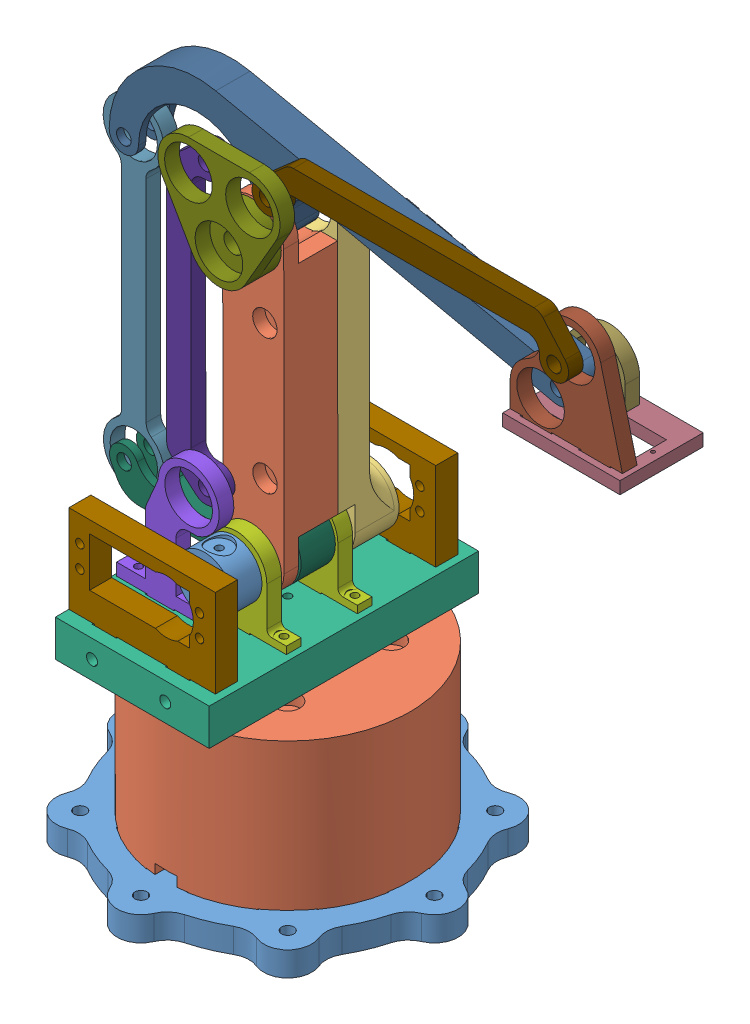
SolidWorks assembly Ensamble completo, configuration Predeterminado. Lengths in mm.
Overall size (225.72 266.26 139.5).
23 component instances, 21 part files, 60 mates.
Components (placement in the parent):
- Base_A-1: Base_A [Predeterminado] at (0.4465 -9.1301 139.5) size (139.5 10 139.5)
- Base_B-1: Base_B [Predeterminado] at (0.4465 60.8699 139.5) x (1 0 0) z (0 -1 0) size (100 100 70.09)
- Base_C-1: Base_C [Predeterminado] at (0.4465 22.8699 139.5) x (0.707107 0 0.707107) z (0 1 0) size (79 79 28)
- 30202JR-1: 30202JR [Predeterminado] at (0.4465 60.8699 139.5) x (0.837169 0 0.546944) z (0.546944 0 -0.837169) size (35 11 35)
- Eje_1_tractor-1: Eje_1_tractor [Predeterminado] at (0.4465 38.8699 139.5) x (0.999999 0 0.00137) z (-0.00137 0 0.999999) size (25 33 25)
- Eje_1_plataforma-1: Eje_1_plataforma [Predeterminado] at (0.4465 61.8699 139.5) x (-0.00137 0 0.999999) z (-0.999999 0 -0.00137) size (110 15 66)
- Soporte_eje_2-1: Soporte_eje_2 [Predeterminado] at (0.4657 97.8699 125.5) x (0.999999 0 0.00137) z (0 -1 0) size (41 6 48.5)
- Soporte_eje_2-2: Soporte_eje_2 [Predeterminado] at (0.4259 97.8699 154.5) x (0.999999 0 0.00137) z (0 -1 0) size (41 6 48.5)
- Soporte_paralelas-1: Soporte_paralelas [Predeterminado] at (0.4163 97.8699 161.5) x (0.999999 0 0.00137) z (0 -1 0) size (42 6 70.15)
- Soporte_motor-1: Soporte_motor [Predeterminado] at (20.3786 76.8699 189.0274) x (-0.999999 0 -0.00137) z (0.00137 0 -0.999999) size (60 51 9)
- Soporte_motor-2: Soporte_motor [Predeterminado] at (20.502 76.8699 99.0274) x (-0.999999 0 -0.00137) z (0.00137 0 -0.999999) size (60 51 9)
- Eje_3-1: Eje_3 [Predeterminado] at (118.0441 212.8707 132.6612) x (0.212423 0.977178 0.000291) z (-0.00137 0 0.999999) size (49.75 186.32 15)
- Eje_4_A-1: Eje_4_A [Predeterminado] at (118.0235 212.8707 147.6611) x (0.999999 -0.000184 0.00137) z (-0.00137 0 0.999999) size (46 49.15 6)
- Eje_4_B-1: Eje_4_B [Predeterminado] at (118.0537 212.8707 125.6612) x (0.999999 -0.000184 0.00137) z (-0.00137 0 0.999999) size (25 27.5 6)
- Eje_4_C-1: Eje_4_C [Predeterminado] at (105.555 197.873 122.644) x (-0.00137 0 0.999999) z (0.000184 1 0) size (34 48 5)
- Leva_eje_3-1: Leva_eje_3 [Predeterminado] at (-59.5493 97.8695 136.4178) x (0.999999 0.000852 0.00137) z (-0.00137 0 0.999999) size (25 140 6)
- Panalca_eje_3-1: Panalca_eje_3 [Predeterminado] at (0.4561 97.8699 132.5) x (-0.000007 1 0) z (-0.00137 0 0.999999) size (25 78.5 14)
- Triangulo-1: Triangulo [Predeterminado] at (0.3102 212.8699 167.4998) x (-0.999999 0 -0.00137) z (0.00137 0 -0.999999) size (50 46.65 13)
- Varilla_115mm-1: Varilla_115mm [Predeterminado] at (-12.0823 119.5205 160.4828) x (-0.999999 -0.000852 -0.00137) z (0.00137 0 -0.999999) size (22 127 6)
- Varilla_117mm-1: Varilla_117mm [Predeterminado] at (130.5179 234.519 154.6783) x (0.000012 1 0) z (-0.00137 0 0.999999) size (22 129.69 6)
- eje_3_tractor-1: eje_3_tractor [Predeterminado] at (0.3999 97.8699 173.5) x (-0.707111 0.707102 -0.000969) z (-0.707101 -0.707112 -0.000969) size (23 12 23)
- Eje_2_A-3: Eje_2_A [Predeterminado] at (0.4753 97.8699 118.5) x (0.999999 0.000852 0.00137) z (-0.00137 0 0.999999) size (25 140 32)
- Eje_2_B-3: Eje_2_B [Predeterminado] at (0.4753 97.8699 118.5) x (0.999999 0.000852 0.00137) z (-0.00137 0 0.999999) size (25 140 25)
Mates (geometry in assembly coordinates):
- Coincidente1: coincident anti-aligned: plane of Base_B-1 through (0.4465 50.8699 139.5) normal (0 -1 0); plane of Base_C-1 through (0.4465 50.8699 139.5) normal (0 1 0)
- Concéntrica4: concentric aligned: cylinder of Base_B-1 through (21.6597 60.8699 160.7132) axis (0 -1 0) radius 2; cylinder of Base_C-1 through (21.6597 50.8699 160.7132) axis (0 -1 0) radius 2
- Concéntrica5: concentric anti-aligned: cylinder of Base_A-1 through (0.4465 0.8699 139.5) axis (0 -1 0) radius 50.25; cylinder of Base_B-1 through (0.4465 -9.1301 139.5) axis (0 1 0) radius 50
- Concéntrica6: concentric aligned: cylinder of Base_A-1 through (32.2663 0.8699 171.3198) axis (0 -1 0) radius 2; cylinder of Base_B-1 through (32.2663 20.8699 171.3198) axis (0 -1 0) radius 1.5
- Coincidente2: coincident anti-aligned: plane of Base_A-1 through (0.4465 0.8699 139.5) normal (0 1 0); plane of Base_B-1 through (0.4465 0.8699 139.5) normal (0 -1 0)
- Coincidente3: coincident anti-aligned: plane of Base_C-1 through (0.4465 50.8699 139.5) normal (0 1 0); plane of 30202JR-1 through (0.4465 50.8699 139.5) normal (0 -1 0)
- Concéntrica8: concentric aligned: cylinder of Eje_1_tractor-1 through (0.4465 38.8699 139.5) axis (0 1 0) radius 1.5; cylinder of Eje_1_plataforma-1 through (0.4465 71.8699 139.5) axis (0 1 0) radius 1.5
- Paralelo2: parallel anti-aligned: plane of Eje_1_tractor-1 through (-3.3124 71.8699 145.99) normal (-0.00137 0 0.999999); plane of Eje_1_plataforma-1 through (0.4373 76.8699 146.2117) normal (0.00137 0 -0.999999)
- Coincidente5: coincident anti-aligned: plane of Eje_1_tractor-1 through (0.4465 71.8699 139.5) normal (0 1 0); plane of Eje_1_plataforma-1 through (0.4465 71.8699 139.5) normal (0 -1 0)
- Coincidente6: coincident anti-aligned: plane of 30202JR-1 through (0.4465 61.8699 139.5) normal (0 1 0); plane of Eje_1_plataforma-1 through (0.4465 61.8699 139.5) normal (0 -1 0)
- Concéntrica9: concentric aligned: cylinder of 30202JR-1 through (0.4465 38.5369 139.5) axis (0 -1 0) radius 7.5; cylinder of Eje_1_tractor-1 through (0.4465 61.8699 139.5) axis (0 -1 0) radius 7.875
- Distancia1: distance = 0.5 mm anti-aligned: plane of Soporte_motor-2 through (20.502 76.8699 99.0274) normal (-0.00137 0 0.999999); plane of Eje_1_plataforma-1 through (0.5013 76.8699 99.5) normal (0.00137 0 -0.999999)
- Coincidente8: coincident anti-aligned: plane of Eje_1_plataforma-1 through (0.4465 76.8699 139.5) normal (0 1 0); plane of Soporte_motor-2 through (20.5143 76.8699 90.0275) normal (0 -1 0)
- Concéntrica10: concentric anti-aligned: cylinder of Eje_1_plataforma-1 through (5.4876 69.3699 109.5069) axis (0.00137 0 -0.999999) radius 1.5; cylinder of Soporte_motor-2 through (5.5143 69.3699 90.0069) axis (-0.00137 0 0.999999) radius 1.5
- Distancia2: distance = 0.5 mm anti-aligned: plane of Soporte_motor-1 through (20.3786 76.8699 189.0274) normal (-0.00137 0 0.999999); plane of Eje_1_plataforma-1 through (0.378 76.8699 189.5) normal (0.00137 0 -0.999999)
- Coincidente10: coincident anti-aligned: plane of Eje_1_plataforma-1 through (0.4465 76.8699 139.5) normal (0 1 0); plane of Soporte_motor-1 through (20.391 76.8699 180.0274) normal (0 -1 0)
- Concéntrica11: concentric aligned: cylinder of Eje_1_plataforma-1 through (-24.5946 69.3699 169.4657) axis (-0.00137 0 0.999999) radius 1.5; cylinder of Soporte_motor-1 through (-24.609 69.3699 179.9657) axis (-0.00137 0 0.999999) radius 1.5
- Coincidente11: coincident anti-aligned: plane of Eje_1_plataforma-1 through (0.4465 76.8699 139.5) normal (0 1 0); plane of Soporte_eje_2-1 through (0.4575 76.8699 131.5) normal (0 -1 0)
- Concéntrica12: concentric aligned: cylinder of Eje_1_plataforma-1 through (-16.0384 76.8699 128.4774) axis (0 -1 0) radius 1.5; cylinder of Soporte_eje_2-1 through (-16.0384 82.8699 128.4774) axis (0 -1 0) radius 1.5
- Concéntrica13: concentric aligned: cylinder of Eje_1_plataforma-1 through (16.9616 76.8699 128.5226) axis (0 -1 0) radius 1.5; cylinder of Soporte_eje_2-1 through (16.9616 82.8699 128.5226) axis (0 -1 0) radius 1.5
- Coincidente12: coincident anti-aligned: plane of Eje_1_plataforma-1 through (0.4465 76.8699 139.5) normal (0 1 0); plane of Soporte_eje_2-2 through (0.4177 76.8699 160.5) normal (0 -1 0)
- Concéntrica14: concentric aligned: cylinder of Eje_1_plataforma-1 through (-16.0782 76.8699 157.4774) axis (0 -1 0) radius 1.5; cylinder of Soporte_eje_2-2 through (-16.0782 82.8699 157.4774) axis (0 -1 0) radius 1.5
- Concéntrica15: concentric aligned: cylinder of Eje_1_plataforma-1 through (16.9218 76.8699 157.5226) axis (0 -1 0) radius 1.5; cylinder of Soporte_eje_2-2 through (16.9218 82.8699 157.5226) axis (0 -1 0) radius 1.5
- Coincidente13: coincident anti-aligned: plane of Eje_1_plataforma-1 through (0.4465 76.8699 139.5) normal (0 1 0); plane of Soporte_paralelas-1 through (0.4081 76.8699 167.5) normal (0 -1 0)
- Concéntrica16: concentric anti-aligned: cylinder of Eje_1_plataforma-1 through (-35.5877 60.8699 164.4506) axis (0 1 0) radius 1.5; cylinder of Soporte_paralelas-1 through (-35.5877 82.8699 164.4506) axis (0 -1 0) radius 1.5
- Concéntrica17: concentric anti-aligned: cylinder of Eje_1_plataforma-1 through (-11.5878 60.8699 164.4835) axis (0 1 0) radius 1.5; cylinder of Soporte_paralelas-1 through (-11.5878 82.8699 164.4835) axis (0 -1 0) radius 1.5
- Coincidente32: coincident anti-aligned: plane of Eje_4_B-1 through (118.0436 202.8707 131.6612) normal (-0.000184 -1 0); plane of Eje_4_C-1 through (105.5559 202.873 122.644) normal (0.000184 1 0)
- Distancia22: distance = 0.5 mm anti-aligned: plane of Eje_4_B-1 through (122.5454 212.8699 131.6673) normal (0.999999 -0.000184 0.00137); plane of Eje_4_C-1 through (123.0429 202.8698 132.168) normal (-0.999999 0.000184 -0.00137)
- Distancia23: distance = 0.5 mm anti-aligned: plane of Eje_4_B-1 through (118.0454 212.8707 131.6612) normal (-0.00137 0 0.999999); plane of Eje_4_C-1 through (110.0429 202.8722 132.1502) normal (0.00137 0 -0.999999)
- Distancia17: distance = 0.5 mm anti-aligned: plane of Eje_4_A-1 through (134.5125 197.8677 153.6837) normal (-0.999999 0.000184 -0.00137); plane of Eje_4_C-1 through (134.0127 202.8678 154.1831) normal (0.999999 -0.000184 0.00137)
- Coincidente29: coincident anti-aligned: plane of Eje_4_A-1 through (146.5134 202.8655 153.7002) normal (-0.000184 -1 0); plane of Eje_4_C-1 through (105.5559 202.873 122.644) normal (0.000184 1 0)
- Distancia19: distance = 0.5 mm anti-aligned: plane of Eje_4_A-1 through (130.5275 234.519 147.6783) normal (0.00137 0 -0.999999); plane of Eje_4_C-1 through (134.0223 202.8678 147.1831) normal (-0.00137 0 0.999999)
- Concéntrica18: concentric aligned: cylinder of Eje_3-1 through (118.0249 212.8707 146.6611) axis (0.00137 0 -0.999999) radius 3; cylinder of Eje_4_A-1 through (118.0153 212.8707 153.6611) axis (0.00137 0 -0.999999) radius 9.75
- Distancia3: distance = 1 mm anti-aligned: plane of Eje_3-1 through (118.0249 212.8707 146.6611) normal (-0.00137 0 0.999999); plane of Eje_4_A-1 through (130.5275 234.519 147.6783) normal (0.00137 0 -0.999999)
- Concéntrica21: concentric aligned: cylinder of Triangulo-1 through (-12.1816 234.5205 161.4827) axis (-0.00137 0 0.999999) radius 9.75; cylinder of Varilla_115mm-1 through (-12.172 234.5205 154.4827) axis (-0.00137 0 0.999999) radius 3
- Distancia6: distance = 1 mm anti-aligned: plane of Varilla_115mm-1 through (-12.0823 119.5205 160.4828) normal (-0.00137 0 0.999999); plane of Triangulo-1 through (0.3184 212.8699 161.4998) normal (0.00137 0 -0.999999)
- Concéntrica22: concentric anti-aligned: cylinder of Eje_3-1 through (0.339 212.8699 146.4999) axis (0.00137 0 -0.999999) radius 3; cylinder of Triangulo-1 through (0.328 212.8699 154.4999) axis (-0.00137 0 0.999999) radius 4
- Concéntrica23: concentric anti-aligned: cylinder of Soporte_paralelas-1 through (-12.0919 119.5205 167.4828) axis (0.00137 0 -0.999999) radius 9.75; cylinder of Varilla_115mm-1 through (-12.074 119.5205 154.4829) axis (-0.00137 0 0.999999) radius 3
- Concéntrica24: concentric anti-aligned: cylinder of Triangulo-1 through (12.8184 234.5205 161.517) axis (-0.00137 0 0.999999) radius 9.75; cylinder of Varilla_117mm-1 through (12.8198 234.5205 160.517) axis (0.00137 0 -0.999999) radius 3
- Distancia8: distance = 1 mm anti-aligned: plane of Varilla_117mm-1 through (130.5097 234.519 160.6783) normal (-0.00137 0 0.999999); plane of Triangulo-1 through (0.3184 212.8699 161.4998) normal (0.00137 0 -0.999999)
- Concéntrica25: concentric aligned: cylinder of Eje_4_A-1 through (130.5193 234.519 153.6783) axis (0.00137 0 -0.999999) radius 9.75; cylinder of Varilla_117mm-1 through (130.5097 234.519 160.6783) axis (0.00137 0 -0.999999) radius 3
- Concéntrica26: concentric aligned: cylinder of Leva_eje_3-1 through (-59.5576 97.8695 142.4178) axis (0.00137 0 -0.999999) radius 9.75; cylinder of Panalca_eje_3-1 through (-59.563 97.8695 146.4178) axis (0.00137 0 -0.999999) radius 3
- Distancia9: distance = 1 mm anti-aligned: plane of Leva_eje_3-1 through (-59.5576 97.8695 142.4178) normal (-0.00137 0 0.999999); plane of Panalca_eje_3-1 through (-59.5589 97.8695 143.4178) normal (0.00137 0 -0.999999)
- Concéntrica27: concentric aligned: cylinder of Eje_3-1 through (-59.661 212.8694 146.4176) axis (0.00137 0 -0.999999) radius 3; cylinder of Leva_eje_3-1 through (-59.6555 212.8694 142.4176) axis (0.00137 0 -0.999999) radius 9.75
- Distancia10: distance = 1 mm anti-aligned: plane of Leva_eje_3-1 through (-59.5576 97.8695 142.4178) normal (-0.00137 0 0.999999); plane of Eje_3-1 through (-59.6569 212.8694 143.4176) normal (0.00137 0 -0.999999)
- Concéntrica29: concentric anti-aligned: cylinder of Panalca_eje_3-1 through (0.4369 97.8699 146.5) axis (0.00137 0 -0.999999) radius 3; cylinder of eje_3_tractor-1 through (0.4163 97.8699 161.5) axis (-0.00137 0 0.999999) radius 3
- Distancia11: distance = 1 mm anti-aligned: plane of eje_3_tractor-1 through (0.4163 97.8699 161.5) normal (0.00137 0 -0.999999); plane of Soporte_eje_2-2 through (0.4177 97.8699 160.5) normal (-0.00137 0 0.999999)
- Paralelo4: parallel aligned: plane of Panalca_eje_3-1 through (0.437 85.3699 146.5) normal (0.000007 -1 0); plane of eje_3_tractor-1 through (0.3998 105.8699 173.5) normal (0.000007 -1 0)
- Concéntrica30: concentric anti-aligned: cylinder of Base_B-1 through (0.4465 -9.1301 139.5) axis (0 1 0) radius 50; cylinder of Base_C-1 through (0.4465 50.8699 139.5) axis (0 -1 0) radius 12.5
- Concéntrica31: concentric aligned: cylinder of Base_C-1 through (0.4465 50.8699 139.5) axis (0 -1 0) radius 39.5; cylinder of 30202JR-1 through (0.4465 38.5369 139.5) axis (0 -1 0) radius 17.5
- Concéntrica32: concentric aligned: cylinder of 30202JR-1 through (0.4465 38.5369 139.5) axis (0 -1 0) radius 17.5; cylinder of Eje_1_tractor-1 through (0.4465 61.8699 139.5) axis (0 -1 0) radius 7.875
- Coincidente27: coincident anti-aligned: circle of Eje_2_A-3; cylinder of Eje_2_B-3 through (5.2162 127.8739 106.5065) axis (-0.00137 0 0.999999) radius 2
- Coincidente28: coincident anti-aligned: plane of Eje_2_A-3 through (12.9574 97.8806 131.5171) normal (0.00137 0 -0.999999); plane of Eje_2_B-3 through (0.4575 97.8699 131.5) normal (-0.00137 0 0.999999)
- Concéntrica43: concentric anti-aligned: cylinder of Eje_2_A-3 through (5.1049 182.8739 153.5064) axis (0.00137 0 -0.999999) radius 2; cylinder of Eje_2_B-3 through (5.1693 182.8739 106.5064) axis (-0.00137 0 0.999999) radius 2
- Distancia14: distance = 1 mm anti-aligned: plane of Eje_2_A-3 through (0.4355 97.8699 147.5) normal (0.00137 0 -0.999999); plane of Eje_3-1 through (118.0249 212.8707 146.6611) normal (-0.00137 0 0.999999)
- Concéntrica44: concentric aligned: cylinder of Eje_3-1 through (0.339 212.8699 146.4999) axis (0.00137 0 -0.999999) radius 3; cylinder of Eje_2_A-3 through (0.3294 212.8699 153.4999) axis (0.00137 0 -0.999999) radius 9.75
- Concéntrica45: concentric aligned: cylinder of Soporte_eje_2-1 through (0.4575 97.8699 131.5) axis (0.00137 0 -0.999999) radius 9.75; cylinder of Eje_2_A-3 through (0.4273 97.8699 153.5) axis (0.00137 0 -0.999999) radius 9.75
- Distancia15: distance = 1 mm anti-aligned: plane of Eje_2_A-3 through (0.4273 97.8699 153.5) normal (-0.00137 0 0.999999); plane of Soporte_eje_2-2 through (0.4259 97.8699 154.5) normal (0.00137 0 -0.999999)
- Distancia16: distance = 1 mm anti-aligned: plane of Triangulo-1 through (0.328 212.8699 154.4999) normal (0.00137 0 -0.999999); plane of Eje_2_A-3 through (0.4273 97.8699 153.5) normal (-0.00137 0 0.999999)
- Concéntrica46: concentric aligned: cylinder of Soporte_eje_2-1 through (0.4575 97.8699 131.5) axis (0.00137 0 -0.999999) radius 9.75; cylinder of Panalca_eje_3-1 through (0.4369 97.8699 146.5) axis (0.00137 0 -0.999999) radius 3
